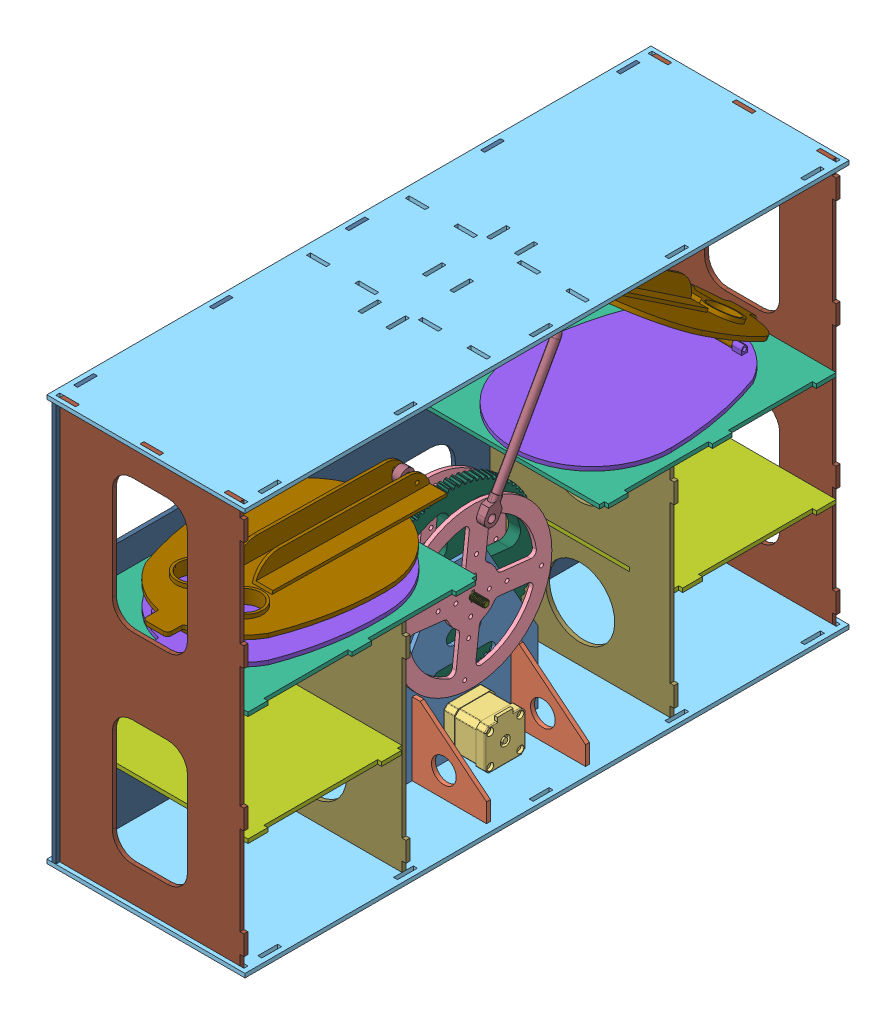
SolidWorks assembly respirador2, configuration Default. Lengths in mm.
Overall size (200 410 619.01).
33 component instances, 17 part files, 115 mates.
Components (placement in the parent):
- frente de motor-1: frente de motor [Default] at (-8.8174 -77.0345 -7.3085) size (4 174 150)
- lateral de motor-1: lateral de motor [Default] at (23.3277 -39.5375 40.6915) x (0 0 1) z (-1 0 0) size (4 77.47 79)
- lateral de motor-2: lateral de motor [Default] at (23.3277 -39.5375 -59.3085) x (0 0 1) z (-1 0 0) size (4 77.47 79)
- nema 17-1: nema 17 [Default] at (37.1826 -46.9473 -7.3085) x (-1 0 0) z (0 0 -1) size (62 45 41)
- rueda-1: rueda [Default] at (0.1826 63.0527 -7.3085) x (1 0 0) z (0 -0.11364 -0.993522) size (4 160 160)
- lateral de motor-3: lateral de motor [Default] at (-64.9624 -39.5375 44.6915) x (0 0 -1) z (1 0 0) size (4 77.47 79)
- frente de motor-2: frente de motor [Default] at (-32.8174 -77.0345 -7.3085) x (-1 0 0) z (0 0 -1) size (4 174 150)
- lateral de motor-4: lateral de motor [Default] at (-64.9624 -39.5375 -55.3085) x (0 0 -1) z (1 0 0) size (4 77.47 79)
- rueda-2: rueda [Default] at (-41.8174 63.0527 -7.3085) x (-1 0 0) z (0 0.11364 0.993522) size (4 160 160)
- nema 17-2: nema 17 [Default] at (-78.8174 -46.9473 -7.3085) size (62 45 41)
- piso 2-1: piso 2 [Default] at (-20.8174 -80.9473 -7.4488) x (0 0 1) z (-1 0 0) size (610 4 200)
- entrepiso-3: entrepiso [Default] at (-21.8174 141.0527 -186.9488) x (0 0 -1) z (1 0 0) size (235 4 190)
- entrepiso-4: entrepiso [Default] at (-19.8174 141.0527 172.0512) x (0 0 1) z (-1 0 0) size (235 4 190)
- piso para electronica-2: piso para electronica [Default] at (-20.8174 30.0527 -222.6438) x (0 0 -1) z (1 0 0) size (163.61 4 190)
- tapa de fuelle-1: tapa de fuelle [Default] at (-19.3174 145.0527 164.5512) x (0 0 1) z (-1 0 0) size (233.07 11.87 160.08)
- tapa de fuelle-2: tapa de fuelle [Default] at (-19.3174 145.0527 -179.4488) x (0 0 -1) z (1 0 0) size (233.07 11.87 160.08)
- tapa sup de fuelle-1: tapa sup de fuelle [Default] at (-19.3174 167.6645 164.8827) x (0 0.015324 0.999883) z (-1 0 0) size (265 43.89 160.08)
- tapa sup de fuelle-2: tapa sup de fuelle [Default] at (-19.3174 216.7725 -204.302) x (0 -0.557561 -0.830136) z (1 0 0) size (265 43.89 160.08)
- lateral-6: lateral [Default] at (-111.8174 89.0527 89.1159) x (-1 0 0) z (0 0 -1) size (4 410 610)
- frentes-4: frentes [Default] at (-20.8174 124.0527 289.5512) size (190 410 4)
- piso 2-4: piso 2 [Default] at (-20.8174 325.0527 -7.4488) x (0 0 1) z (-1 0 0) size (610 4 200)
- soporte de entrepiso-3: soporte de entrepiso [Default] at (-20.8174 61.0527 -144.8388) x (1 0 0) z (0 -1 0) size (190 4 222)
- frentes-5: frentes [Default] at (-20.8174 124.0527 -308.4488) size (190 410 4)
- bastago-3: bastago [Default] at (-22.3174 204.7887 -50.0325) x (1 0 0) z (0 0.483797 0.87518) size (38.86 205 15)
- bastago-4: bastago [Default] at (-16.3174 72.8116 12.0856) x (-1 0 0) z (0 0.198075 -0.980187) size (38.86 205 15)
- soporte de entrepiso-4: soporte de entrepiso [Default] at (-20.8174 61.0527 125.9412) x (1 0 0) z (0 -1 0) size (190 4 222)
- piso para electronica-3: piso para electronica [Default] at (-20.8174 30.0527 207.7462) x (0 0 1) z (-1 0 0) size (163.61 4 190)
- pinon-1: pinon [Default] at (-29.8174 -46.9473 -7.3085) x (1 0 0) z (0 0 -1) size (18 54.8 54.93)
- Corona-1: Corona [Default] at (-27.8174 63.0527 -7.3085) x (1 0 0) z (0 0.11364 0.993522) size (12 170.97 170.26)
- eje principal-1: eje principal [Default] at (18.4326 63.0527 -7.3085) x (0 0.11364 0.993522) z (-1 0 0) size (7.18 7.27 81.79)
- perno de eje-1: perno de eje [Default] at (-21.5674 58.0649 -6.738) x (0.331957 0.107196 0.937184) z (-0.943295 0.037724 0.329806) size (2.5 10 2.5)
- perno de eje-2: perno de eje [Default] at (-45.0674 58.0851 -6.7403) x (0.978308 0.023541 0.205812) z (-0.207154 0.111175 0.971971) size (2.5 10 2.5)
- perno de eje-3: perno de eje [Default] at (1.9326 58.0851 -6.7403) x (0.835502 0.062444 0.545927) z (-0.549487 0.094947 0.83009) size (2.5 10 2.5)
Mates (geometry in assembly coordinates):
- Parallel1: parallel: plane of frente de motor-1 through (-4.8174 -77.0345 -7.3085) normal (1 0 0); plane of lateral de motor-1 through (-4.8174 -25.4846 44.6915) normal (-1 0 0)
- Coincident1: coincident: plane of frente de motor-1 through (-4.8174 -5.4846 44.6915) normal (0 0 -1); plane of lateral de motor-1 through (23.3277 -39.5375 44.6915) normal (0 0 1)
- Coincident2: coincident: plane of frente de motor-1 through (-4.8174 -5.4846 44.6915) normal (0 -1 0); plane of lateral de motor-1 through (-8.8174 -5.4846 44.6915) normal (0 1 0)
- Coincident3: coincident: plane of frente de motor-1 through (-4.8174 -77.0345 -7.3085) normal (1 0 0); plane of lateral de motor-1 through (-4.8174 -25.4846 44.6915) normal (-1 0 0)
- Parallel2: parallel: plane of frente de motor-1 through (-4.8174 -77.0345 -7.3085) normal (1 0 0); plane of lateral de motor-2 through (-4.8174 -25.4846 -55.3085) normal (-1 0 0)
- Coincident4: coincident: plane of frente de motor-1 through (-4.8174 -5.4846 -59.3085) normal (0 -1 0); plane of lateral de motor-2 through (-8.8174 -5.4846 -55.3085) normal (0 1 0)
- Coincident5: coincident: plane of frente de motor-1 through (-4.8174 -25.4846 -59.3085) normal (0 0 1); plane of lateral de motor-2 through (23.3277 -39.5375 -59.3085) normal (0 0 -1)
- Coincident6: coincident: plane of frente de motor-1 through (-4.8174 -77.0345 -7.3085) normal (1 0 0); plane of lateral de motor-2 through (-4.8174 -25.4846 -55.3085) normal (-1 0 0)
- Concentric1: concentric: cylinder of frente de motor-1 through (-4.8174 -46.9473 -7.3085) axis (-1 0 0) radius 11; cylinder of nema 17-1 through (-7.8174 -46.9473 -7.3085) axis (1 0 0) radius 11
- Concentric2: concentric: cylinder of frente de motor-1 through (-4.8174 -31.0374 8.6014) axis (-1 0 0) radius 1.75; cylinder of nema 17-1 through (-0.8174 -31.0374 8.6014) axis (-1 0 0) radius 1.5
- Coincident7: coincident: plane of frente de motor-1 through (-4.8174 -77.0345 -7.3085) normal (1 0 0); plane of nema 17-1 through (-4.8174 -46.9473 -7.3085) normal (-1 0 0)
- Concentric3: concentric: cylinder of frente de motor-1 through (-4.8174 63.0527 -7.3085) axis (-1 0 0) radius 10; cylinder of rueda-1 through (4.1826 63.0527 -7.3085) axis (-1 0 0) radius 3
- Distance1: distance = 5 mm: plane of rueda-1 through (0.1826 63.0527 -7.3085) normal (-1 0 0); plane of frente de motor-1 through (-4.8174 -77.0345 -7.3085) normal (1 0 0)
- Parallel3: parallel: plane of ? through (-351.9923 -70.7004 99.5076) normal (0 0 1); plane of ? through (-93.6666 165.2996 90.5076) normal (0 0 -1)
- Coincident11: coincident: plane of ? through (-211.9923 -70.7004 94.5076) normal (0 0 -1); plane of ? through (-93.6666 165.2996 94.5076) normal (0 0 1)
- Coincident12: coincident: plane of ? through (-331.9923 -70.7004 94.5076) normal (1 0 0); plane of ? through (-331.9923 -74.7004 90.5076) normal (-1 0 0)
- Coincident13: coincident: plane of ? through (-21.9923 -70.7004 -0.4924) normal (0 1 0); plane of ? through (148.0077 -70.7004 90.5076) normal (0 -1 0)
- Concentric4: concentric: cylinder of frente de motor-2 through (-36.8174 -46.9473 -7.3085) axis (1 0 0) radius 11; cylinder of nema 17-2 through (-75.8174 -46.9473 -7.3085) axis (-1 0 0) radius 5
- Concentric5: concentric: cylinder of frente de motor-2 through (-36.8174 -31.0374 -23.2184) axis (1 0 0) radius 1.75; cylinder of nema 17-2 through (-40.8174 -31.0374 -23.2184) axis (1 0 0) radius 1.5
- Coincident14: coincident: plane of frente de motor-2 through (-36.8174 -77.0345 -7.3085) normal (-1 0 0); plane of nema 17-2 through (-36.8174 -46.9473 -7.3085) normal (1 0 0)
- Parallel4: parallel: plane of ? through (-93.6666 165.2996 90.5076) normal (0 0 -1); plane of ? through (-93.6666 165.2996 -91.4924) normal (0 0 1)
- Coincident15: coincident: plane of ? through (-331.9923 -70.7004 -91.4924) normal (0 0 -1); plane of ? through (-93.6666 165.2996 -91.4924) normal (0 0 1)
- Coincident16: coincident: plane of ? through (-21.9923 -70.7004 -0.4924) normal (0 1 0); plane of ? through (-211.9923 -70.7004 -95.4924) normal (0 -1 0)
- Coincident17: coincident: plane of ? through (-331.9923 -70.7004 -95.4924) normal (1 0 0); plane of ? through (-331.9923 -74.7004 -95.4924) normal (-1 0 0)
- Parallel5: parallel: plane of ? through (-21.9923 -70.7004 -0.4924) normal (0 1 0); plane of ? through (-229.4923 201.2996 -1.4924) normal (0 -1 0)
- Parallel6: parallel: plane of ? through (-93.6666 165.2996 90.5076) normal (0 0 -1); plane of ? through (-241.9923 201.2996 90.5076) normal (0 0 1)
- Coincident18: coincident: plane of ? through (-346.9923 205.2996 -95.4924) normal (0 -1 0); plane of ? through (-229.4923 205.2996 -1.4924) normal (0 1 0)
- Coincident19: coincident: plane of ? through (-346.9923 205.2996 90.5076) normal (1 0 0); plane of ? through (-346.9923 201.2996 -95.4924) normal (-1 0 0)
- Coincident20: coincident: plane of ? through (-93.6666 165.2996 90.5076) normal (0 0 -1); plane of ? through (-241.9923 201.2996 90.5076) normal (0 0 1)
- Coincident21: coincident: plane of ? through (-229.4923 205.2996 -1.4924) normal (0 1 0); plane of ? through (-183.3866 205.2996 49.5076) normal (0 1 0)
- Coincident22: coincident: plane of ? through (-187.3866 171.2996 -95.4924) normal (1 0 0); plane of ? through (-187.3866 67.2996 -0.4924) normal (-1 0 0)
- Coincident25: coincident: plane of ? through (-93.6666 165.2996 -91.4924) normal (0 0 1); plane of ? through (-183.3866 191.2996 -91.4924) normal (0 0 -1)
- Coincident26: coincident: plane of ? through (-183.3866 65.2996 49.5076) normal (0 -1 0); plane of ? through (-265.1916 65.2996 -0.4924) normal (0 1 0)
- Coincident27: coincident: plane of ? through (-183.3866 67.2996 -0.4924) normal (1 0 0); plane of ? through (-183.3866 65.2996 -50.4924) normal (1 0 0)
- Coincident28: coincident: plane of ? through (-93.6666 165.2996 -91.4924) normal (0 0 1); plane of ? through (-211.9923 65.2996 -91.4924) normal (0 0 -1)
- Parallel9: parallel: plane of ? through (303.0077 205.2996 -95.4924) normal (-1 0 0); plane of ? through (305.3575 201.2996 94.5076) normal (1 0 0)
- Coincident37: coincident: plane of lateral de motor-4 through (-62.8174 -76.9473 -59.3085) normal (0 -1 0); plane of piso 2-1 through (-20.8174 -76.9473 -7.4488) normal (0 1 0)
- Coincident38: coincident: plane of frente de motor-2 through (-32.8174 -77.0345 -7.3085) normal (1 0 0); plane of piso 2-1 through (-32.8174 -76.9473 -82.3085) normal (-1 0 0)
- Concentric6: concentric: cylinder of tapa de fuelle-1 through (-74.3174 153.0527 255.5785) axis (1 0 0) radius 2; cylinder of tapa sup de fuelle-1 through (14.6826 153.0527 255.5785) axis (-1 0 0) radius 2
- Coincident65: coincident: plane of tapa de fuelle-1 through (-44.3174 157.0527 252.5785) normal (1 0 0); plane of tapa sup de fuelle-1 through (-44.3174 151.0506 250.9969) normal (-1 0 0)
- Concentric7: concentric: cylinder of tapa de fuelle-2 through (35.6826 153.0527 -270.4762) axis (-1 0 0) radius 2; cylinder of tapa sup de fuelle-2 through (-53.3174 153.0527 -270.4762) axis (1 0 0) radius 2
- Coincident66: coincident: plane of tapa de fuelle-2 through (5.6826 157.0527 -267.4762) normal (-1 0 0); plane of tapa sup de fuelle-2 through (5.6826 148.9365 -267.6376) normal (1 0 0)
- Concentric8: concentric: cylinder of tapa sup de fuelle-2 through (-54.3174 268.122 -88.2395) axis (1 0 0) radius 2; cylinder of ? through (-16.3174 268.122 -88.2395) axis (-1 0 0) radius 3.8245
- Concentric11: concentric: cylinder of tapa sup de fuelle-1 through (15.6826 331.438 103.4198) axis (-1 0 0) radius 2; cylinder of ? through (-24.3174 331.438 103.4198) axis (1 0 0) radius 3.8245
- Distance8: distance = 5 mm: plane of ? through (-24.3174 268.122 -88.2395) normal (-1 0 0); plane of tapa sup de fuelle-2 through (-29.3174 254.3802 -251.3656) normal (1 0 0)
- Concentric12: concentric: cylinder of rueda-1 through (4.1826 49.0117 -68.474) axis (-1 0 0) radius 2; cylinder of ? through (13.6826 49.0117 -68.474) axis (-1 0 0) radius 3.8245
- Concentric13: concentric: cylinder of rueda-1 through (4.1826 117.0936 53.857) axis (-1 0 0) radius 2; cylinder of ? through (-54.3174 117.0936 53.857) axis (1 0 0) radius 3.8245
- Distance9: distance = 5 mm: plane of ? through (-24.3174 331.438 103.4198) normal (-1 0 0); plane of tapa sup de fuelle-1 through (-29.3174 266.8437 253.841) normal (1 0 0)
- Coincident70: coincident: plane of piso 2-1 through (74.1826 -76.9473 282.5512) normal (0 0 1); plane of ? through (74.1826 -6.9473 282.4416) normal (0 0 -1)
- Coincident77: coincident: plane of ? through (74.1826 159.0527 -79.1232) normal (1 0 0); plane of ? through (74.1826 119.0527 318.5512) normal (1 0 0)
- Parallel11: parallel: plane of ? through (70.1826 159.0527 -79.1232) normal (-1 0 0); plane of ? through (74.1826 269.0527 318.5512) normal (1 0 0)
- Coincident93: coincident: plane of piso 2-1 through (-20.8174 -76.9473 -7.4488) normal (0 1 0); plane of ? through (-120.9365 -66.0489 -310.4717) normal (0 -1 0)
- Coincident95: coincident: plane of piso 2-1 through (-115.8174 -76.9473 -272.4488) normal (1 0 0); plane of ? through (-115.8174 89.0527 -108.6743) normal (-1 0 0)
- Coincident96: coincident: plane of piso 2-1 through (-111.8174 -76.9473 -295.1096) normal (0 0 1); plane of ? through (-111.8174 -80.9473 -295.1096) normal (0 0 -1)
- Coincident97: coincident: plane of piso 2-1 through (-20.8174 -76.9473 -7.4488) normal (0 1 0); plane of ? through (-111.8174 -76.9473 -158.1096) normal (0 -1 0)
- Coincident98: coincident: plane of piso 2-1 through (-111.8174 -76.9473 -272.4488) normal (-1 0 0); plane of lateral-6 through (-111.8174 89.0527 89.1159) normal (1 0 0)
- Coincident99: coincident: plane of piso 2-1 through (-20.8174 -76.9473 -7.4488) normal (0 1 0); plane of lateral-6 through (-115.8174 -76.9473 138.5512) normal (0 -1 0)
- Coincident100: coincident: plane of piso 2-1 through (-111.8174 -76.9473 275.5512) normal (0 0 -1); plane of lateral-6 through (-115.8174 -80.9473 275.5512) normal (0 0 1)
- Coincident104: coincident: plane of frente de motor-1 through (-4.8174 -4.998 -82.3085) normal (0 0 -1); plane of piso 2-1 through (-8.8174 -76.9473 -82.3085) normal (0 0 1)
- Coincident105: coincident: plane of lateral-6 through (-111.8174 89.0527 89.1159) normal (1 0 0); plane of frentes-4 through (-111.8174 124.0527 293.5512) normal (-1 0 0)
- Coincident106: coincident: plane of lateral-6 through (-115.8174 315.0527 293.5512) normal (0 -1 0); plane of frentes-4 through (-20.8174 315.0527 293.5512) normal (0 1 0)
- Coincident107: coincident: plane of lateral-6 through (-115.8174 315.0527 289.5512) normal (0 0 1); plane of frentes-4 through (-20.8174 124.0527 289.5512) normal (0 0 -1)
- Coincident108: coincident: plane of lateral-6 through (-115.8174 325.0527 -272.4488) normal (0 1 0); plane of ? through (-20.8174 325.0527 -179.1675) normal (0 -1 0)
- Coincident109: coincident: plane of lateral-6 through (-111.8174 89.0527 89.1159) normal (1 0 0); plane of ? through (-111.8174 325.0527 85.8325) normal (-1 0 0)
- Parallel13: parallel: plane of lateral-6 through (-115.8174 89.0527 89.1159) normal (-1 0 0); plane of piso 2-4 through (79.1826 329.0527 -312.4488) normal (1 0 0)
- Coincident111: coincident: plane of lateral-6 through (-115.8174 325.0527 255.5512) normal (0 0 -1); plane of piso 2-4 through (-115.8174 329.0527 255.5512) normal (0 0 1)
- Coincident112: coincident: plane of lateral-6 through (-115.8174 89.0527 89.1159) normal (-1 0 0); plane of piso 2-4 through (-115.8174 329.0527 255.5512) normal (1 0 0)
- Coincident113: coincident: plane of lateral-6 through (-115.8174 325.0527 297.5512) normal (0 1 0); plane of piso 2-4 through (-20.8174 325.0527 -7.4488) normal (0 -1 0)
- Coincident117: coincident: plane of entrepiso-3 through (-111.8174 145.0527 -199.4488) normal (-1 0 0); plane of lateral-6 through (-111.8174 89.0527 89.1159) normal (1 0 0)
- Coincident118: coincident: plane of entrepiso-3 through (-115.8174 145.0527 -304.4488) normal (0 0 -1); plane of lateral-6 through (-115.8174 145.0527 -304.4488) normal (0 0 1)
- Coincident119: coincident: plane of entrepiso-3 through (-21.8174 145.0527 -186.9488) normal (0 1 0); plane of lateral-6 through (-115.8174 145.0527 -304.4488) normal (0 -1 0)
- Coincident121: coincident: plane of entrepiso-3 through (-21.8174 141.0527 -186.9488) normal (0 -1 0); plane of soporte de entrepiso-3 through (-111.8174 141.0527 -140.8388) normal (0 1 0)
- Coincident122: coincident: plane of entrepiso-3 through (-70.8174 145.0527 -144.8388) normal (0 0 1); plane of soporte de entrepiso-3 through (-20.8174 61.0527 -144.8388) normal (0 0 -1)
- Coincident123: coincident: plane of lateral-6 through (-111.8174 89.0527 89.1159) normal (1 0 0); plane of soporte de entrepiso-3 through (-111.8174 -46.9473 -140.8388) normal (-1 0 0)
- Coincident125: coincident: plane of piso para electronica-2 through (-111.8174 34.0527 -169.4445) normal (-1 0 0); plane of lateral-6 through (-111.8174 89.0527 89.1159) normal (1 0 0)
- Coincident126: coincident: plane of piso para electronica-2 through (70.1826 34.0527 -144.8388) normal (0 0 1); plane of soporte de entrepiso-3 through (-20.8174 61.0527 -144.8388) normal (0 0 -1)
- Coincident127: coincident: plane of piso para electronica-2 through (-20.8174 34.0527 -222.6438) normal (0 1 0); plane of soporte de entrepiso-3 through (-70.8174 34.0527 -140.8388) normal (0 -1 0)
- Coincident128: coincident: plane of entrepiso-3 through (-115.8174 145.0527 -304.4488) normal (0 0 -1); plane of tapa de fuelle-2 through (-27.8174 149.0527 -304.4488) normal (0 0 -1)
- Coincident129: coincident: plane of entrepiso-3 through (-21.8174 145.0527 -186.9488) normal (0 1 0); plane of tapa de fuelle-2 through (165.0472 145.0527 -157.8348) normal (0 -1 0)
- Distance10: distance = 80 mm: plane of tapa de fuelle-2 through (-31.8174 149.0527 -290.1066) normal (-1 0 0); plane of lateral-6 through (-111.8174 89.0527 89.1159) normal (1 0 0)
- Coincident130: coincident: plane of entrepiso-4 through (-19.8174 145.0527 172.0512) normal (0 1 0); plane of lateral-6 through (-115.8174 145.0527 289.5512) normal (0 -1 0)
- Coincident131: coincident: plane of entrepiso-4 through (-111.8174 145.0527 59.5512) normal (0 0 -1); plane of lateral-6 through (-115.8174 145.0527 59.5512) normal (0 0 1)
- Coincident132: coincident: plane of entrepiso-4 through (-111.8174 145.0527 79.5512) normal (-1 0 0); plane of lateral-6 through (-111.8174 89.0527 89.1159) normal (1 0 0)
- Coincident133: coincident: plane of entrepiso-4 through (-19.8174 145.0527 172.0512) normal (0 1 0); plane of tapa de fuelle-1 through (-203.6819 145.0527 142.9372) normal (0 -1 0)
- Coincident134: coincident: plane of entrepiso-4 through (74.1826 145.0527 289.5512) normal (0 0 1); plane of tapa de fuelle-1 through (-10.8174 149.0527 289.5512) normal (0 0 1)
- Distance11: distance = 80 mm: plane of tapa de fuelle-1 through (-31.8174 149.0527 285.5512) normal (-1 0 0); plane of lateral-6 through (-111.8174 89.0527 89.1159) normal (1 0 0)
- Coincident135: coincident: plane of lateral-6 through (-115.8174 205.0527 -304.4488) normal (0 0 -1); plane of frentes-5 through (-20.8174 124.0527 -304.4488) normal (0 0 1)
- Coincident136: coincident: plane of lateral-6 through (-111.8174 89.0527 89.1159) normal (1 0 0); plane of frentes-5 through (-111.8174 124.0527 -304.4488) normal (-1 0 0)
- Coincident137: coincident: plane of piso 2-4 through (-20.8174 325.0527 -7.4488) normal (0 -1 0); plane of frentes-5 through (-20.8174 325.0527 -304.4488) normal (0 1 0)
- Concentric14: concentric: cylinder of tapa sup de fuelle-2 through (-54.3174 174.4207 -52.5948) axis (1 0 0) radius 2; cylinder of bastago-3 through (-14.3174 174.4207 -52.5948) axis (-1 0 0) radius 3.8245
- Distance12: distance = 5 mm: plane of bastago-3 through (-14.3174 298.8814 -107.1885) normal (1 0 0); plane of tapa sup de fuelle-2 through (-9.3174 216.0784 -248.4068) normal (-1 0 0)
- Concentric15: concentric: cylinder of rueda-1 through (4.1826 -4.11 12.4189) axis (-1 0 0) radius 2; cylinder of bastago-3 through (15.6826 -4.11 12.4189) axis (-1 0 0) radius 3.8245
- Concentric16: concentric: cylinder of tapa sup de fuelle-1 through (15.6826 286.0424 81.6744) axis (-1 0 0) radius 2; cylinder of bastago-4 through (-24.3174 286.0424 81.6744) axis (1 0 0) radius 3.8245
- Distance13: distance = 5 mm: plane of bastago-4 through (-24.3174 179.7408 38.2846) normal (-1 0 0); plane of tapa sup de fuelle-1 through (-29.3174 192.2436 201.5104) normal (1 0 0)
- Concentric17: concentric: cylinder of rueda-1 through (4.1826 130.2154 -27.0359) axis (-1 0 0) radius 2; cylinder of bastago-4 through (-54.3174 130.2154 -27.0359) axis (1 0 0) radius 3.8245
- Coincident138: coincident: plane of entrepiso-4 through (-19.8174 141.0527 172.0512) normal (0 -1 0); plane of soporte de entrepiso-4 through (29.1826 141.0527 129.9412) normal (0 1 0)
- Coincident139: coincident: plane of lateral-6 through (-115.8174 -66.9473 125.9412) normal (0 0 1); plane of soporte de entrepiso-4 through (-20.8174 61.0527 125.9412) normal (0 0 -1)
- Coincident140: coincident: plane of lateral-6 through (-111.8174 89.0527 89.1159) normal (1 0 0); plane of soporte de entrepiso-4 through (-111.8174 -46.9473 129.9412) normal (-1 0 0)
- Coincident141: coincident: plane of soporte de entrepiso-4 through (-20.8174 61.0527 129.9412) normal (0 0 1); plane of piso para electronica-3 through (-111.8174 34.0527 129.9412) normal (0 0 -1)
- Coincident142: coincident: plane of lateral-6 through (-115.8174 34.0527 154.5512) normal (0 -1 0); plane of piso para electronica-3 through (-20.8174 34.0527 207.7462) normal (0 1 0)
- Coincident143: coincident: plane of lateral-6 through (-111.8174 89.0527 89.1159) normal (1 0 0); plane of piso para electronica-3 through (-111.8174 34.0527 154.5469) normal (-1 0 0)
- Concentric19: concentric: cylinder of rueda-1 through (4.1826 63.0527 -7.3085) axis (-1 0 0) radius 3; cylinder of Corona-1 through (-15.8174 63.0527 -7.3085) axis (-1 0 0) radius 3.5
- Parallel14: parallel: plane of rueda-1 through (10.1826 58.6076 -4.7001) normal (0 -0.281821 -0.959467); plane of Corona-1 through (-27.8174 72.9996 -8.9274) normal (0 -0.281821 -0.959467)
- Concentric20: concentric: cylinder of nema 17-1 through (-24.8174 -46.9473 -7.3085) axis (1 0 0) radius 2.5; cylinder of pinon-1 through (-11.8174 -46.9473 -7.3085) axis (-1 0 0) radius 2.5
- Distance14: distance = 3 mm: plane of pinon-1 through (-29.8174 -46.9473 -7.3085) normal (-1 0 0); plane of frente de motor-2 through (-32.8174 -77.0345 -7.3085) normal (1 0 0)
- Distance15: distance = 5 mm: plane of Corona-1 through (-27.8174 63.0527 -7.3085) normal (-1 0 0); plane of frente de motor-2 through (-32.8174 -77.0345 -7.3085) normal (1 0 0)
- GearMate1: gear = 49 : 165 mm: cylinder of Corona-1 through (-15.8174 63.0527 -7.3085) axis (-1 0 0) radius 82.5; cylinder of pinon-1 through (-11.8174 -46.9473 -7.3085) axis (-1 0 0) radius 24.5
- Concentric21: concentric: cylinder of rueda-1 through (4.1826 63.0527 -7.3085) axis (-1 0 0) radius 3; cylinder of eje principal-1 through (-61.5674 63.0527 -7.3085) axis (1 0 0) radius 3.5
- Concentric22: concentric: cylinder of eje principal-1 through (-21.5674 53.458 -4.4903) axis (0 0.959467 -0.281821) radius 1.25; cylinder of perno de eje-1 through (-21.5674 60.354 -6.5158) axis (0 0.959467 -0.281821) radius 1.25
- Tangent1: tangent: plane of rueda-1 through (10.1826 58.6076 -4.7001) normal (0 -0.281821 -0.959467); cylinder of perno de eje-1 through (-21.5674 60.354 -6.5158) axis (0 0.959467 -0.281821) radius 1.25
- Distance16: distance = 5 mm: cylinder of perno de eje-1 through (-21.5674 68.0001 -7.8744) axis (0 -0.993522 0.11364) radius 1.25; plane of Corona-1 through (-27.8174 63.0527 -7.3085) normal (-1 0 0)
- Concentric23: concentric: cylinder of eje principal-1 through (-45.0674 53.458 -4.4903) axis (0 0.959467 -0.281821) radius 1.25; cylinder of perno de eje-2 through (-45.0674 58.2553 -5.8994) axis (0 0.959467 -0.281821) radius 1.25
- Coincident144: coincident: plane of rueda-2 through (-51.8174 58.6076 -4.7001) normal (0 0.959467 -0.281821); plane of perno de eje-2 through (-45.0674 58.2553 -5.8994) normal (0 -0.959467 0.281821)
- Concentric24: concentric: cylinder of eje principal-1 through (1.9326 53.458 -4.4903) axis (0 0.959467 -0.281821) radius 1.25; cylinder of perno de eje-3 through (1.9326 58.2553 -5.8994) axis (0 0.959467 -0.281821) radius 1.25
- Coincident145: coincident: plane of rueda-1 through (10.1826 67.4977 -9.9169) normal (0 -0.959467 0.281821); plane of perno de eje-3 through (1.9326 67.85 -8.7176) normal (0 0.959467 -0.281821)
